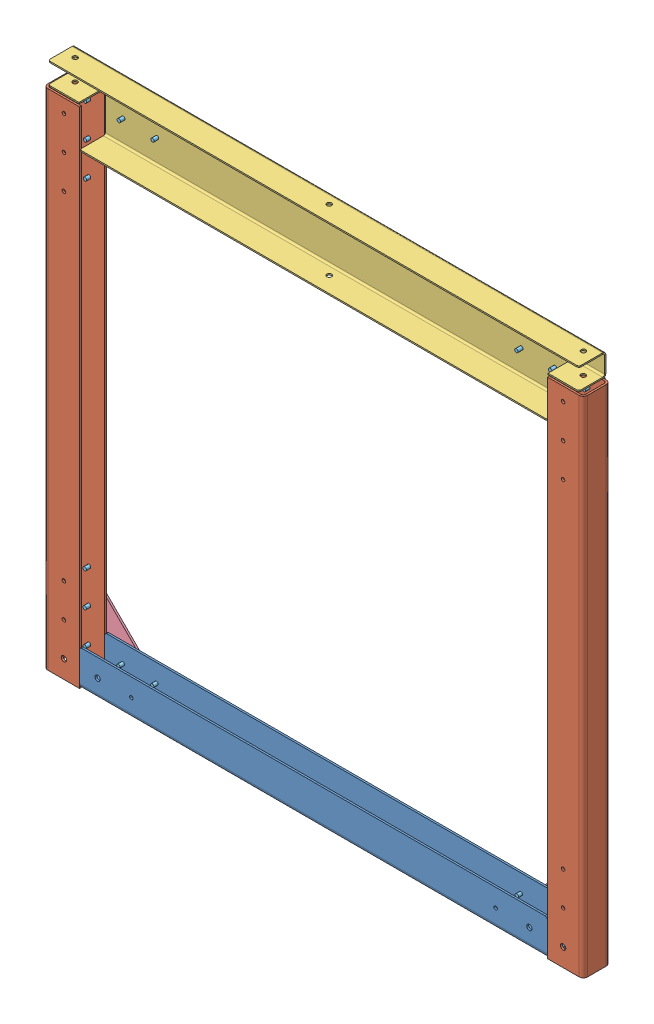
SolidWorks assembly GE-20101, configuration Default. Lengths in mm.
Overall size (762 746.12 42.88).
28 component instances, 5 part files, 60 mates.
Components (placement in the parent):
- GE-20101-02-1: GE-20101-02 [Default] at (-63.586 365.2467 773.1396) size (660.4 50.8 38.1)
- GE-20101-03-1: GE-20101-03 [right] at (693.334 976.1188 738.2146) x (0 0 1) z (1 0 0) size (38.1 711.2 50.8)
- GE-20101-03-2: GE-20101-03 [Default] at (-68.666 976.1188 776.3146) x (0 0 -1) z (-1 0 0) size (38.1 711.2 50.8)
- GE-20101-01-1: GE-20101-01 [Default] at (-62.316 1000.7648 740.1119) size (749.3 88.9 38.1)
- GE-20101-04-1: GE-20101-04 [Default] at (-59.141 946.7898 735.0396) x (1 0 0) z (0 -1 0) size (127 2.66 127)
- GE-20101-04-2: GE-20101-04 [Default] at (-59.141 495.9398 738.2146) x (1 0 0) z (0 1 0) size (127 2.66 127)
- GE-20101-04-3: GE-20101-04 [Default] at (683.809 946.7898 738.2146) x (-1 0 0) z (0 -1 0) size (127 2.66 127)
- GE-20101-04-4: GE-20101-04 [Default] at (683.809 495.9398 735.0396) x (-1 0 0) z (0 1 0) size (127 2.66 127)
- rivet_.1875_.126-.25-76: rivet_.1875_.126-.25 [Default] at (7.534 387.9898 735.5577) x (-0.923728 -0.383049 0) z (0 0 -1) size (10.01 10.01 13.03)
- rivet_.1875_.126-.25-69: rivet_.1875_.126-.25 [Default] at (55.159 387.9898 735.5577) x (-0.923728 -0.383049 0) z (0 0 -1) size (10.01 10.01 13.03)
- rivet_.1875_.126-.25-79: rivet_.1875_.126-.25 [Default] at (-40.091 387.9898 735.5577) x (-0.923728 -0.383049 0) z (0 0 -1) size (10.01 10.01 13.03)
- rivet_.1875_.126-.25-77: rivet_.1875_.126-.25 [Default] at (-40.091 435.6148 735.5577) x (-0.923728 -0.383049 0) z (0 0 -1) size (10.01 10.01 13.03)
- rivet_.1875_.126-.25-78: rivet_.1875_.126-.25 [Default] at (-40.091 483.2398 735.5577) x (-0.923728 -0.383049 0) z (0 0 -1) size (10.01 10.01 13.03)
- rivet_.1875_.126-.25-80: rivet_.1875_.126-.25 [Default] at (-40.091 959.4898 735.0396) x (-0.923728 -0.383049 0) z (0 0 -1) size (10.01 10.01 13.03)
- rivet_.1875_.126-.25-70: rivet_.1875_.126-.25 [Default] at (-40.091 1007.1148 735.0396) x (-0.923728 -0.383049 0) z (0 0 -1) size (10.01 10.01 13.03)
- rivet_.1875_.126-.25-71: rivet_.1875_.126-.25 [Default] at (-40.091 1054.7398 735.0396) x (-0.923728 -0.383049 0) z (0 0 -1) size (10.01 10.01 13.03)
- rivet_.1875_.126-.25-72: rivet_.1875_.126-.25 [Default] at (55.159 1054.7398 735.0396) x (-0.923728 -0.383049 0) z (0 0 -1) size (10.01 10.01 13.03)
- rivet_.1875_.126-.25-73: rivet_.1875_.126-.25 [Default] at (7.534 1054.7398 735.0396) x (-0.923728 -0.383049 0) z (0 0 -1) size (10.01 10.01 13.03)
- rivet_.1875_.126-.25-74: rivet_.1875_.126-.25 [Default] at (664.759 959.4898 735.5577) x (-0.923728 -0.383049 0) z (0 0 -1) size (10.01 10.01 13.03)
- rivet_.1875_.126-.25-75: rivet_.1875_.126-.25 [Default] at (664.759 1007.1148 735.5577) x (-0.923728 -0.383049 0) z (0 0 -1) size (10.01 10.01 13.03)
- rivet_.1875_.126-.25-82: rivet_.1875_.126-.25 [Default] at (664.759 1054.7398 735.5577) x (-0.923728 -0.383049 0) z (0 0 -1) size (10.01 10.01 13.03)
- rivet_.1875_.126-.25-85: rivet_.1875_.126-.25 [Default] at (617.134 1054.7398 735.5577) x (-0.923728 -0.383049 0) z (0 0 -1) size (10.01 10.01 13.03)
- rivet_.1875_.126-.25-86: rivet_.1875_.126-.25 [Default] at (569.509 1054.7398 735.5577) x (-0.923728 -0.383049 0) z (0 0 -1) size (10.01 10.01 13.03)
- rivet_.1875_.126-.25-84: rivet_.1875_.126-.25 [Default] at (664.759 435.6148 735.0396) x (-0.923728 -0.383049 0) z (0 0 -1) size (10.01 10.01 13.03)
- rivet_.1875_.126-.25-87: rivet_.1875_.126-.25 [Default] at (664.759 483.2398 735.0396) x (-0.923728 -0.383049 0) z (0 0 -1) size (10.01 10.01 13.03)
- rivet_.1875_.126-.25-88: rivet_.1875_.126-.25 [Default] at (664.759 387.9898 735.0396) x (-0.923728 -0.383049 0) z (0 0 -1) size (10.01 10.01 13.03)
- rivet_.1875_.126-.25-81: rivet_.1875_.126-.25 [Default] at (617.134 387.9898 735.0396) x (-0.923728 -0.383049 0) z (0 0 -1) size (10.01 10.01 13.03)
- rivet_.1875_.126-.25-83: rivet_.1875_.126-.25 [Default] at (569.509 387.9898 735.0396) x (-0.923728 -0.383049 0) z (0 0 -1) size (10.01 10.01 13.03)
Mates (geometry in assembly coordinates):
- Distance1: distance = 762 mm anti-aligned: plane of GE-20101-03-1 through (693.334 976.1188 738.2146) normal (1 0 0); plane of GE-20101-03-2 through (-68.666 976.1188 776.3146) normal (-1 0 0)
- Coincident7: coincident aligned: plane of GE-20101-02-1 through (-63.586 362.5898 773.1396) normal (0 -1 0); plane of GE-20101-03-2 through (-68.666 362.5898 738.2146) normal (0 -1 0)
- Coincident9: coincident aligned: plane of GE-20101-02-1 through (-63.586 362.5898 773.1396) normal (0 -1 0); plane of GE-20101-03-1 through (693.334 362.5898 776.3146) normal (0 -1 0)
- Coincident10: coincident aligned: plane of GE-20101-02-1 through (-63.586 365.2467 738.2146) normal (0 0 -1); plane of GE-20101-03-1 through (693.334 976.1188 738.2146) normal (0 0 -1)
- Coincident11: coincident aligned: plane of GE-20101-02-1 through (-63.586 365.2467 738.2146) normal (0 0 -1); plane of GE-20101-03-2 through (-68.666 976.1188 738.2146) normal (0 0 -1)
- Concentric3: concentric anti-aligned: cylinder of GE-20101-03-1 through (664.759 959.4898 776.3146) axis (0 0 1) radius 2.4574; cylinder of GE-20101-04-3 through (664.759 959.4898 735.5577) axis (0 0 -1) radius 2.4574
- Concentric4: concentric anti-aligned: cylinder of GE-20101-03-1 through (664.759 1007.1148 776.3146) axis (0 0 1) radius 2.4574; cylinder of GE-20101-04-3 through (664.759 1007.1148 735.5577) axis (0 0 -1) radius 2.4574
- Concentric5: concentric anti-aligned: cylinder of GE-20101-03-2 through (-40.091 959.4898 738.2146) axis (0 0 -1) radius 2.4574; cylinder of GE-20101-04-1 through (-40.091 959.4898 737.6964) axis (0 0 1) radius 2.4574
- Concentric6: concentric anti-aligned: cylinder of GE-20101-03-2 through (-40.091 1007.1148 738.2146) axis (0 0 -1) radius 2.4574; cylinder of GE-20101-04-1 through (-40.091 1007.1148 737.6964) axis (0 0 1) radius 2.4574
- Concentric7: concentric aligned: cylinder of GE-20101-03-2 through (-40.091 387.9898 738.2146) axis (0 0 -1) radius 2.4574; cylinder of GE-20101-04-2 through (-40.091 387.9898 735.5577) axis (0 0 -1) radius 2.4574
- Concentric8: concentric aligned: cylinder of GE-20101-03-2 through (-40.091 435.6148 738.2146) axis (0 0 -1) radius 2.4574; cylinder of GE-20101-04-2 through (-40.091 435.6148 735.5577) axis (0 0 -1) radius 2.4574
- Coincident12: coincident anti-aligned: plane of GE-20101-02-1 through (-17.866 362.5898 738.2146) normal (-1 0 0); plane of GE-20101-03-2 through (-17.866 1073.7898 738.2146) normal (1 0 0)
- Concentric9: concentric aligned: cylinder of GE-20101-03-1 through (664.759 387.9898 776.3146) axis (0 0 1) radius 2.4574; cylinder of GE-20101-04-4 through (664.759 387.9898 737.6964) axis (0 0 1) radius 2.4574
- Concentric10: concentric aligned: cylinder of GE-20101-03-1 through (664.759 435.6148 776.3146) axis (0 0 1) radius 2.4574; cylinder of GE-20101-04-4 through (664.759 435.6148 737.6964) axis (0 0 1) radius 2.4574
- Coincident13: coincident anti-aligned: plane of GE-20101-03-1 through (693.334 976.1188 738.2146) normal (0 0 -1); plane of GE-20101-04-3 through (683.809 946.7898 738.2146) normal (0 0 1)
- Distance2: distance = 741.3625 mm anti-aligned: plane of SM top rail-1 through (-62.316 1108.7148 740.1119) normal (0 1 0); plane of SM cross leg-1 through (-63.586 362.5898 773.1396) normal (0 -1 0)
- Coincident15: coincident: plane of SM Leg-1 through (642.534 1073.7898 776.3146) normal (-1 0 0); plane of SM top rail-1 through (642.534 1021.9478 776.3146) normal (1 0 0)
- Coincident16: coincident anti-aligned: plane of GE-20101-03-2 through (-17.866 1073.7898 776.3146) normal (1 0 0); plane of GE-20101-01-1 through (-17.866 1019.8148 740.1119) normal (-1 0 0)
- Coincident17: coincident aligned: plane of GE-20101-03-2 through (-68.666 976.1188 776.3146) normal (0 0 1); plane of GE-20101-01-1 through (-17.866 1019.8148 776.3146) normal (0 0 1)
- Distance3: distance = 3.175 mm anti-aligned: plane of GE-20101-03-2 through (-66.0091 1073.7898 738.2146) normal (0 1 0); plane of GE-20101-01-1 through (-62.316 1076.9648 740.1119) normal (0 -1 0)
- Coincident20: coincident anti-aligned: plane of GE-20101-04-4 through (683.809 495.9398 735.0396) normal (0 0 -1); plane of rivet_.1875_.126-.25-81 through (617.134 387.9898 735.0396) normal (0 0 1)
- Coincident21: coincident anti-aligned: plane of GE-20101-04-4 through (683.809 495.9398 735.0396) normal (0 0 -1); plane of rivet_.1875_.126-.25-83 through (569.509 387.9898 735.0396) normal (0 0 1)
- Coincident22: coincident anti-aligned: plane of GE-20101-04-4 through (683.809 495.9398 735.0396) normal (0 0 -1); plane of rivet_.1875_.126-.25-81 through (617.134 387.9898 735.0396) normal (0 0 1)
- Coincident23: coincident anti-aligned: plane of GE-20101-04-4 through (683.809 495.9398 735.0396) normal (0 0 -1); plane of rivet_.1875_.126-.25-87 through (664.759 483.2398 735.0396) normal (0 0 1)
- Coincident24: coincident anti-aligned: plane of GE-20101-04-4 through (683.809 495.9398 735.0396) normal (0 0 -1); plane of rivet_.1875_.126-.25-88 through (664.759 387.9898 735.0396) normal (0 0 1)
- Concentric11: concentric anti-aligned: cylinder of GE-20101-04-4 through (664.759 387.9898 737.6964) axis (0 0 1) radius 2.4574; cylinder of rivet_.1875_.126-.25-88 through (664.759 387.9898 746.4696) axis (0 0 -1) radius 2.3813
- Concentric12: concentric anti-aligned: cylinder of GE-20101-04-4 through (569.509 387.9898 737.6964) axis (0 0 1) radius 2.4574; cylinder of rivet_.1875_.126-.25-83 through (569.509 387.9898 746.4696) axis (0 0 -1) radius 2.3813
- Concentric13: concentric anti-aligned: cylinder of GE-20101-04-4 through (617.134 387.9898 737.6964) axis (0 0 1) radius 2.4574; cylinder of rivet_.1875_.126-.25-81 through (617.134 387.9898 746.4696) axis (0 0 -1) radius 2.3813
- Concentric14: concentric anti-aligned: cylinder of GE-20101-04-4 through (664.759 435.6148 737.6964) axis (0 0 1) radius 2.4574; cylinder of rivet_.1875_.126-.25-84 through (664.759 435.6148 746.4696) axis (0 0 -1) radius 2.3813
- Concentric15: concentric anti-aligned: cylinder of GE-20101-04-4 through (664.759 483.2398 737.6964) axis (0 0 1) radius 2.4574; cylinder of rivet_.1875_.126-.25-87 through (664.759 483.2398 746.4696) axis (0 0 -1) radius 2.3813
- Coincident25: coincident anti-aligned: plane of GE-20101-04-3 through (683.809 946.7898 735.5577) normal (0 0 -1); plane of rivet_.1875_.126-.25-82 through (664.759 1054.7398 735.5577) normal (0 0 1)
- Coincident26: coincident anti-aligned: plane of GE-20101-04-3 through (683.809 946.7898 735.5577) normal (0 0 -1); plane of rivet_.1875_.126-.25-75 through (664.759 1007.1148 735.5577) normal (0 0 1)
- Coincident27: coincident anti-aligned: plane of GE-20101-04-3 through (683.809 946.7898 735.5577) normal (0 0 -1); plane of rivet_.1875_.126-.25-85 through (617.134 1054.7398 735.5577) normal (0 0 1)
- Coincident28: coincident anti-aligned: plane of GE-20101-04-3 through (683.809 946.7898 735.5577) normal (0 0 -1); plane of rivet_.1875_.126-.25-86 through (569.509 1054.7398 735.5577) normal (0 0 1)
- Coincident29: coincident anti-aligned: plane of GE-20101-04-3 through (683.809 946.7898 735.5577) normal (0 0 -1); plane of rivet_.1875_.126-.25-74 through (664.759 959.4898 735.5577) normal (0 0 1)
- Concentric16: concentric aligned: cylinder of GE-20101-04-3 through (664.759 959.4898 735.5577) axis (0 0 -1) radius 2.4574; cylinder of rivet_.1875_.126-.25-74 through (664.759 959.4898 746.9877) axis (0 0 -1) radius 2.3813
- Concentric17: concentric aligned: cylinder of GE-20101-04-3 through (664.759 1007.1148 735.5577) axis (0 0 -1) radius 2.4574; cylinder of rivet_.1875_.126-.25-75 through (664.759 1007.1148 746.9877) axis (0 0 -1) radius 2.3813
- Concentric18: concentric aligned: cylinder of GE-20101-04-3 through (664.759 1054.7398 735.5577) axis (0 0 -1) radius 2.4574; cylinder of rivet_.1875_.126-.25-82 through (664.759 1054.7398 746.9877) axis (0 0 -1) radius 2.3813
- Concentric19: concentric aligned: cylinder of GE-20101-04-3 through (617.134 1054.7398 735.5577) axis (0 0 -1) radius 2.4574; cylinder of rivet_.1875_.126-.25-85 through (617.134 1054.7398 746.9877) axis (0 0 -1) radius 2.3813
- Concentric20: concentric aligned: cylinder of GE-20101-04-3 through (569.509 1054.7398 735.5577) axis (0 0 -1) radius 2.4574; cylinder of rivet_.1875_.126-.25-86 through (569.509 1054.7398 746.9877) axis (0 0 -1) radius 2.3813
- Coincident30: coincident anti-aligned: plane of GE-20101-04-1 through (-59.141 946.7898 735.0396) normal (0 0 -1); plane of rivet_.1875_.126-.25-73 through (7.534 1054.7398 735.0396) normal (0 0 1)
- Coincident31: coincident anti-aligned: plane of GE-20101-04-1 through (-59.141 946.7898 735.0396) normal (0 0 -1); plane of rivet_.1875_.126-.25-72 through (55.159 1054.7398 735.0396) normal (0 0 1)
- Coincident32: coincident anti-aligned: plane of GE-20101-04-1 through (-59.141 946.7898 735.0396) normal (0 0 -1); plane of rivet_.1875_.126-.25-71 through (-40.091 1054.7398 735.0396) normal (0 0 1)
- Coincident33: coincident aligned: plane of GE-20101-04-1 through (-59.141 946.7898 735.0396) normal (0 0 -1); circle of 97525A430_18-8 STAINLESS STEEL BLIND RIVETS-7
- Coincident34: coincident anti-aligned: plane of GE-20101-04-1 through (-59.141 946.7898 735.0396) normal (0 0 -1); plane of rivet_.1875_.126-.25-80 through (-40.091 959.4898 735.0396) normal (0 0 1)
- Concentric21: concentric anti-aligned: cylinder of GE-20101-04-1 through (7.534 1054.7398 737.6964) axis (0 0 1) radius 2.4574; cylinder of rivet_.1875_.126-.25-73 through (7.534 1054.7398 746.4696) axis (0 0 -1) radius 2.3813
- Concentric22: concentric anti-aligned: cylinder of GE-20101-04-1 through (55.159 1054.7398 737.6964) axis (0 0 1) radius 2.4574; cylinder of rivet_.1875_.126-.25-72 through (55.159 1054.7398 746.4696) axis (0 0 -1) radius 2.3813
- Concentric23: concentric anti-aligned: cylinder of GE-20101-04-1 through (-40.091 1054.7398 737.6964) axis (0 0 1) radius 2.4574; cylinder of rivet_.1875_.126-.25-71 through (-40.091 1054.7398 746.4696) axis (0 0 -1) radius 2.3813
- Concentric24: concentric anti-aligned: cylinder of GE-20101-04-1 through (-40.091 1007.1148 737.6964) axis (0 0 1) radius 2.4574; cylinder of rivet_.1875_.126-.25-70 through (-40.091 1007.1148 746.4696) axis (0 0 -1) radius 2.3813
- Concentric25: concentric anti-aligned: cylinder of GE-20101-04-1 through (-40.091 959.4898 737.6964) axis (0 0 1) radius 2.4574; cylinder of rivet_.1875_.126-.25-80 through (-40.091 959.4898 746.4696) axis (0 0 -1) radius 2.3813
- Coincident35: coincident anti-aligned: plane of GE-20101-04-2 through (-59.141 495.9398 735.5577) normal (0 0 -1); plane of rivet_.1875_.126-.25-76 through (7.534 387.9898 735.5577) normal (0 0 1)
- Coincident36: coincident anti-aligned: plane of GE-20101-04-2 through (-59.141 495.9398 735.5577) normal (0 0 -1); plane of rivet_.1875_.126-.25-69 through (55.159 387.9898 735.5577) normal (0 0 1)
- Coincident37: coincident anti-aligned: plane of GE-20101-04-2 through (-59.141 495.9398 735.5577) normal (0 0 -1); plane of rivet_.1875_.126-.25-79 through (-40.091 387.9898 735.5577) normal (0 0 1)
- Coincident38: coincident anti-aligned: plane of GE-20101-04-2 through (-59.141 495.9398 735.5577) normal (0 0 -1); plane of rivet_.1875_.126-.25-77 through (-40.091 435.6148 735.5577) normal (0 0 1)
- Coincident39: coincident anti-aligned: plane of GE-20101-04-2 through (-59.141 495.9398 735.5577) normal (0 0 -1); plane of rivet_.1875_.126-.25-78 through (-40.091 483.2398 735.5577) normal (0 0 1)
- Concentric26: concentric aligned: cylinder of GE-20101-04-2 through (-40.091 483.2398 735.5577) axis (0 0 -1) radius 2.4574; cylinder of rivet_.1875_.126-.25-78 through (-40.091 483.2398 746.9877) axis (0 0 -1) radius 2.3813
- Concentric27: concentric aligned: cylinder of GE-20101-04-2 through (-40.091 435.6148 735.5577) axis (0 0 -1) radius 2.4574; cylinder of rivet_.1875_.126-.25-77 through (-40.091 435.6148 746.9877) axis (0 0 -1) radius 2.3813
- Concentric28: concentric aligned: cylinder of GE-20101-04-2 through (-40.091 387.9898 735.5577) axis (0 0 -1) radius 2.4574; cylinder of rivet_.1875_.126-.25-79 through (-40.091 387.9898 746.9877) axis (0 0 -1) radius 2.3813
- Concentric29: concentric aligned: cylinder of GE-20101-04-2 through (7.534 387.9898 735.5577) axis (0 0 -1) radius 2.4574; cylinder of rivet_.1875_.126-.25-76 through (7.534 387.9898 746.9877) axis (0 0 -1) radius 2.3813
- Concentric30: concentric aligned: cylinder of GE-20101-04-2 through (55.159 387.9898 735.5577) axis (0 0 -1) radius 2.4574; cylinder of rivet_.1875_.126-.25-69 through (55.159 387.9898 746.9877) axis (0 0 -1) radius 2.3813
